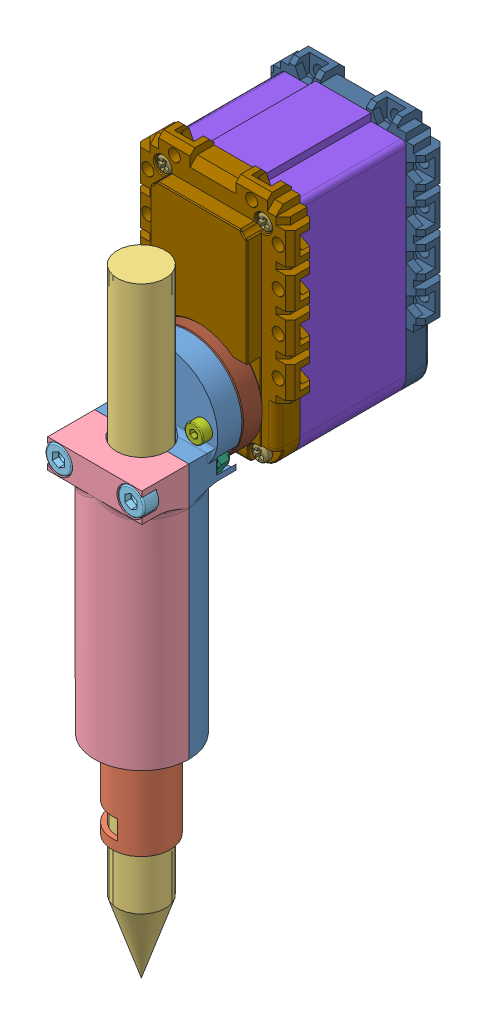
SolidWorks assembly ass_support_stylo, configuration Défaut. Lengths in mm.
Overall size (32 138.59 59.5).
20 component instances, 13 part files, 24 mates.
Components (placement in the parent):
- support_stylo_mot1-1: support_stylo_mot1 [Défaut] at (-32.143 23.7524 58.2179) size (22 67.09 9.75)
- support_stylo-1: support_stylo [Défaut] at (-32.1236 -30.3405 68.0805) x (0.985494 0 -0.169709) z (0 1 0) size (13.5 15 52)
- stylo-1: stylo [Défaut] at (-32.1236 51.6595 68.0805) x (0.760702 0 0.649101) z (0 -1 0) size (10 10 128)
- support_stylo_mot2-1: support_stylo_mot2 [Défaut] at (-22.393 20.6595 77.7179) x (-1 0 0) z (0 -1 0) size (19.5 9.75 53)
- socket head cap screw 4762_din-1: socket head cap screw 4762_din [EN ISO 4762 M3 x 16 - 16N] at (-39.643 17.6595 77.7179) x (0 0 -1) z (1 0 0) size (19 5.5 5.5)
- socket head cap screw 4762_din-2: socket head cap screw 4762_din [EN ISO 4762 M3 x 16 - 16N] at (-24.643 17.6595 77.7179) x (0 0 -1) z (1 0 0) size (19 5.5 5.5)
- hex nut style 1 gradeab_din-1: hex nut style 1 gradeab_din [Hexagon Nut ISO 4032 - M3 - W - N] at (-24.9028 17.8095 62.2179) x (0.866025 -0.5 0) z (0 0 1) size (5.5 6.35 2.4)
- hex nut style 1 gradeab_din-2: hex nut style 1 gradeab_din [Hexagon Nut ISO 4032 - M3 - W - N] at (-39.3832 17.8095 62.2179) x (0.866025 -0.5 0) z (0 0 1) size (5.5 6.35 2.4)
- socket head cap screw_din-1: socket head cap screw_din [DIN 912 M2 x 8 --- 8N] at (-24.143 23.7524 65.2179) x (0 0 -1) z (1 0 0) size (10 3.8 3.8)
- socket head cap screw_din-2: socket head cap screw_din [DIN 912 M2 x 8 --- 8N] at (-40.143 23.7524 65.2179) x (0 0 -1) z (1 0 0) size (10 3.8 3.8)
- AX-12A-1: AX-12A [Default] at (-32.143 23.7524 37.2179) x (0 1 0) z (0 0 1) size (50 32 40.55)
  - AX-12A-01-1: AX-12A-01 [Default] at origin size (48.5 26 22)
  - AX-12A-02-1: AX-12A-02 [Default] at (0 0 13.5) size (50 32 8)
  - AX-12A-03-1: AX-12A-03 [Default] at (0 0 -13.5) x (1 0 0) z (0 0 -1) size (50 32 8)
  - AX-12A-04-1: AX-12A-04 [Default] at (0 0 21) size (22 22 6.7)
  - SetScrew-5: SetScrew [Default] at (33 10.4 14.5) x (0.31498 0.949098 0) z (0 0 -1) size (3.3 3.3 29.44)
  - SetScrew-6: SetScrew [Default] at (-9 9.25 14.5) x (0.31498 0.949098 0) z (0 0 -1) size (3.3 3.3 29.44)
  - SetScrew-7: SetScrew [Default] at (-9 -9.25 14.5) x (-0.958559 0.284893 0) z (0 0 -1) size (3.3 3.3 29.44)
  - SetScrew-8: SetScrew [Default] at (33 -10.4 14.5) x (0.31498 0.949098 0) z (0 0 -1) size (3.3 3.3 29.44)
  - pan head cross recess screw_iso-1: pan head cross recess screw_iso [ISO 7045 - M2.5 x 8 - Z --- 8C] at (0 0 21.6) x (0 0 -1) z (1 0 0) size (10.05 5 5)
Mates (geometry in assembly coordinates):
- Coaxiale1: concentric anti-aligned: cylinder of support_stylo_mot1-1 through (-32.143 -30.3405 67.9679) axis (0 1 0) radius 7.75; cylinder of support_stylo-1 through (-32.143 1.6595 67.9679) axis (0 -1 0) radius 6
- Coïncidente1: coincident anti-aligned: plane of support_stylo_mot1-1 through (-32.143 -30.3405 67.9679) normal (0 1 0); plane of support_stylo-1 through (-32.1236 -30.3405 68.0805) normal (0 -1 0)
- Coaxiale2: concentric anti-aligned: cylinder of support_stylo-1 through (-32.1236 -28.3405 68.0805) axis (0 -1 0) radius 5; cylinder of stylo-1 through (-32.1236 -76.3405 68.0805) axis (0 1 0) radius 5
- Distance1: distance = 50 mm aligned: plane of support_stylo-1 through (-32.143 1.6595 67.9679) normal (0 1 0); plane of stylo-1 through (-32.1236 51.6595 68.0805) normal (0 1 0)
- Coaxiale3: concentric anti-aligned: cylinder of support_stylo_mot1-1 through (-24.643 17.6595 58.2179) axis (0 0 1) radius 1.75; cylinder of support_stylo_mot2-1 through (-24.643 17.6595 77.7179) axis (0 0 -1) radius 1.75
- Coaxiale6: concentric anti-aligned: cylinder of support_stylo_mot1-1 through (-39.643 17.6595 58.2179) axis (0 0 1) radius 1.75; cylinder of support_stylo_mot2-1 through (-39.643 17.6595 77.7179) axis (0 0 -1) radius 1.75
- Coïncidente2: coincident anti-aligned: plane of support_stylo_mot1-1 through (-24.393 -30.3405 67.9679) normal (0 0 1); plane of support_stylo_mot2-1 through (-37.393 14.6595 67.9679) normal (0 0 -1)
- Coaxiale7: concentric anti-aligned: cylinder of support_stylo_mot2-1 through (-24.643 17.6595 77.7179) axis (0 0 -1) radius 1.75; cylinder of socket head cap screw 4762_din-2 through (-24.643 17.6595 109.4679) axis (0 0 1) radius 1.5
- Coaxiale8: concentric anti-aligned: cylinder of support_stylo_mot2-1 through (-39.643 17.6595 77.7179) axis (0 0 -1) radius 1.75; cylinder of socket head cap screw 4762_din-1 through (-39.643 17.6595 109.4679) axis (0 0 1) radius 1.5
- Coïncidente3: coincident anti-aligned: plane of support_stylo_mot2-1 through (-24.643 17.6595 74.7179) normal (0 0 1); plane of socket head cap screw 4762_din-2 through (-24.643 20.4095 74.7179) normal (0 0 -1)
- Coïncidente4: coincident anti-aligned: plane of support_stylo_mot2-1 through (-39.643 17.6595 74.7179) normal (0 0 1); plane of socket head cap screw 4762_din-1 through (-39.643 20.4095 74.7179) normal (0 0 -1)
- Coïncidente5: coincident anti-aligned: plane of support_stylo_mot1-1 through (-26.3173 20.5595 62.2179) normal (0 -1 0); plane of hex nut style 1 gradeab_din-1 through (-23.3151 20.5595 59.8179) normal (0 1 0)
- Coïncidente6: coincident anti-aligned: plane of support_stylo_mot1-1 through (-41.3173 20.5595 62.2179) normal (0 -1 0); plane of hex nut style 1 gradeab_din-2 through (-37.7955 20.5595 59.8179) normal (0 1 0)
- Coïncidente7: coincident anti-aligned: plane of support_stylo_mot1-1 through (-32.143 23.7524 62.2179) normal (0 0 -1); plane of hex nut style 1 gradeab_din-1 through (-23.3151 20.5595 62.2179) normal (0 0 1)
- Coïncidente8: coincident anti-aligned: plane of support_stylo_mot1-1 through (-32.143 23.7524 62.2179) normal (0 0 -1); plane of hex nut style 1 gradeab_din-2 through (-37.7955 20.5595 62.2179) normal (0 0 1)
- Coïncidente9: coincident anti-aligned: plane of support_stylo_mot1-1 through (-36.2944 17.6595 62.2179) normal (-0.866025 0.5 0); plane of hex nut style 1 gradeab_din-2 through (-36.2078 17.8095 59.8179) normal (0.866025 -0.5 0)
- Coïncidente10: coincident anti-aligned: plane of support_stylo_mot1-1 through (-26.3173 14.7595 62.2179) normal (0.866025 0.5 0); plane of hex nut style 1 gradeab_din-1 through (-28.0782 17.8095 59.8179) normal (-0.866025 -0.5 0)
- Coaxiale11: concentric anti-aligned: cylinder of support_stylo_mot1-1 through (-24.143 23.7524 63.2179) axis (0 0 -1) radius 1.25; cylinder of socket head cap screw_din-1 through (-24.143 23.7524 96.9679) axis (0 0 1) radius 1
- Coaxiale12: concentric anti-aligned: cylinder of support_stylo_mot1-1 through (-40.143 23.7524 63.2179) axis (0 0 -1) radius 1.25; cylinder of socket head cap screw_din-2 through (-40.143 23.7524 96.9679) axis (0 0 1) radius 1
- Coïncidente11: coincident anti-aligned: plane of support_stylo_mot1-1 through (-32.143 23.7524 63.2179) normal (0 0 1); plane of socket head cap screw_din-1 through (-24.143 25.6524 63.2179) normal (0 0 -1)
- Coïncidente12: coincident anti-aligned: plane of support_stylo_mot1-1 through (-32.143 23.7524 63.2179) normal (0 0 1); plane of socket head cap screw_din-2 through (-40.143 25.6524 63.2179) normal (0 0 -1)
- Coaxiale13: concentric aligned: cylinder of socket head cap screw_din-2 through (-40.143 23.7524 96.9679) axis (0 0 1) radius 1; cylinder of AX-12A-1/AX-12A-04-1 through (-40.143 23.7524 58.2179) axis (0 0 1) radius 0.8
- Coaxiale14: concentric aligned: cylinder of socket head cap screw_din-1 through (-24.143 23.7524 96.9679) axis (0 0 1) radius 1; cylinder of AX-12A-1/AX-12A-04-1 through (-24.143 23.7524 58.2179) axis (0 0 1) radius 0.8
- Coïncidente13: coincident anti-aligned: plane of support_stylo_mot1-1 through (-32.143 23.7524 58.2179) normal (0 0 -1); plane of AX-12A-1/AX-12A-04-1 through (-34.893 23.7524 58.2179) normal (0 0 1)
